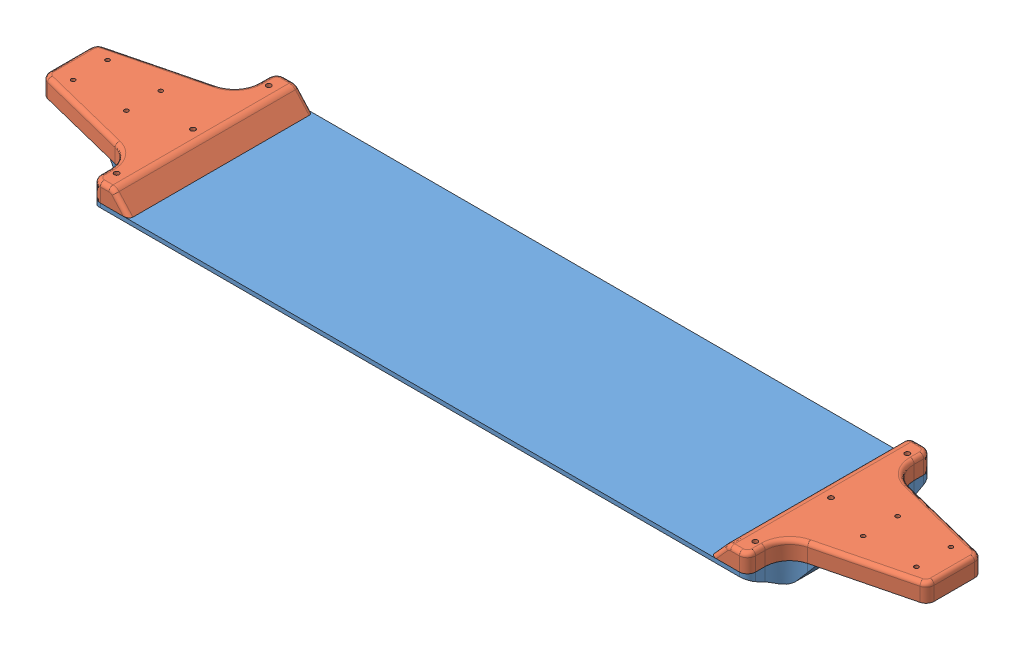
SolidWorks assembly asembly longboard, configuration Default. Lengths in mm.
Overall size (1079.62 47 225).
3 component instances, 2 part files, 6 mates.
Components (placement in the parent):
- board-1: board [Default] at (-37.1124 400.9325 758.7222) size (860 25 225)
- wheel part-1: wheel part [Default] at (-146.9213 425.9325 646.2222) size (184.81 22 225)
- wheel part-2: wheel part [Default] at (932.6965 425.9325 646.2222) x (-1 0 0) z (0 0 -1) size (184.81 22 225)
Mates (geometry in assembly coordinates):
- Coincident2: coincident anti-aligned: plane of board-1 through (-37.1124 425.9325 758.7222) normal (0 1 0); plane of wheel part-1 through (-146.9213 425.9325 646.2222) normal (0 -1 0)
- Coincident3: coincident anti-aligned: plane of board-1 through (-37.1124 425.9325 758.7222) normal (0 1 0); plane of wheel part-2 through (932.6965 425.9325 646.2222) normal (0 -1 0)
- Distance1: distance = 75 mm: line of wheel part-2 through (747.8876 425.9325 753.7222) axis (0 0 -1); plane of board-1 through (822.8876 425.9325 758.7222) normal (1 0 0)
- Coincident4: coincident aligned: plane of board-1 through (-37.1124 425.9325 758.7222) normal (0 0 1); plane of wheel part-2 through (792.6965 447.9325 758.7222) normal (0 0 1)
- Coincident5: coincident aligned: plane of board-1 through (-37.1124 425.9325 758.7222) normal (0 0 1); plane of wheel part-1 through (-6.9213 447.9325 758.7222) normal (0 0 1)
- Distance2: distance = 75 mm: line of wheel part-1 through (37.8876 425.9325 538.7222) axis (0 0 1); plane of board-1 through (-37.1124 425.9325 758.7222) normal (-1 0 0)
